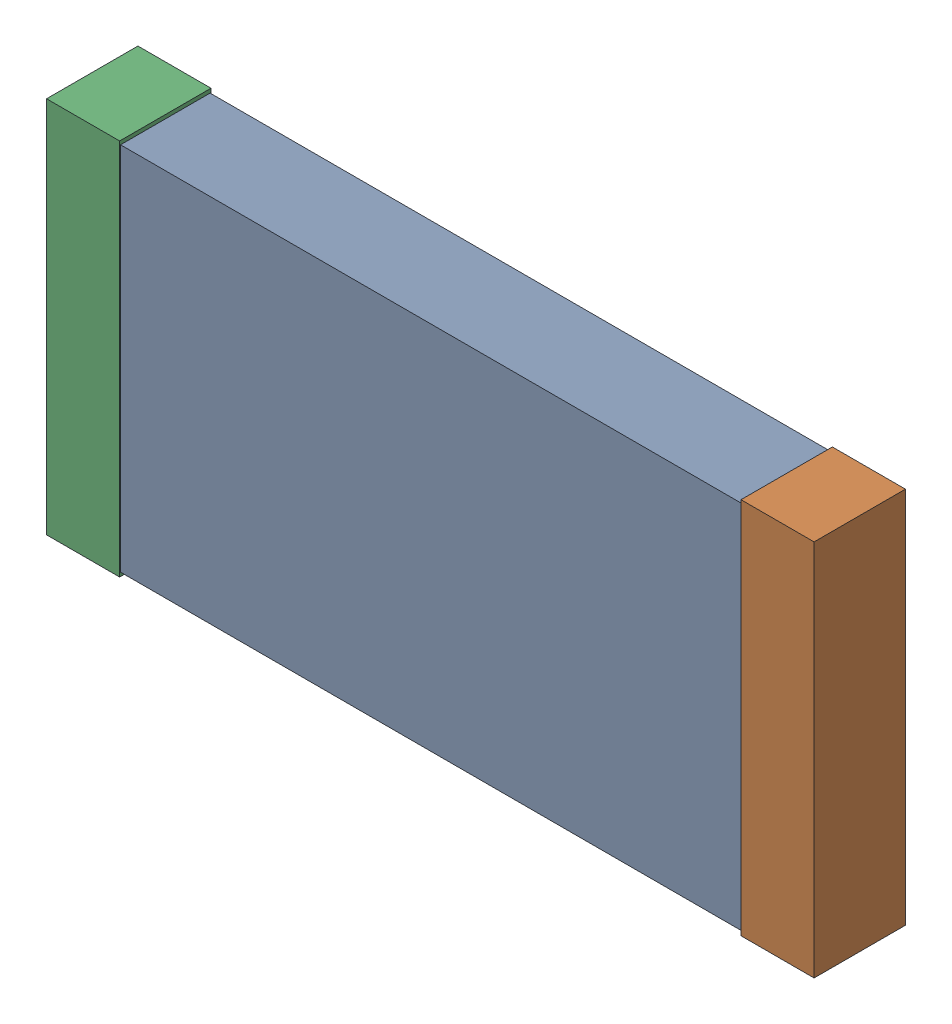
SolidWorks assembly R1, configuration 默认. Lengths in mm.
Overall size (6.3 3.1 0.75).
4 component instances, 3 part files, 0 mates.
Components (placement in the parent):
- 6132022016-1: 6132022016 [默认] at (8.763 10.033 -1.6914) x (1 0 0) z (0 0 -1) size (6.3 3.1 0.75)
  - body-1-1: body-1 [默认] at (-2.55 -1.519 0.0075) size (5.1 3.04 0.73)
  - term2-1: term2 [默认] at (2.55 -1.55 0) size (0.6 3.1 0.75)
  - term1-1: term1 [默认] at (-3.15 -1.55 0) size (0.6 3.1 0.75)
